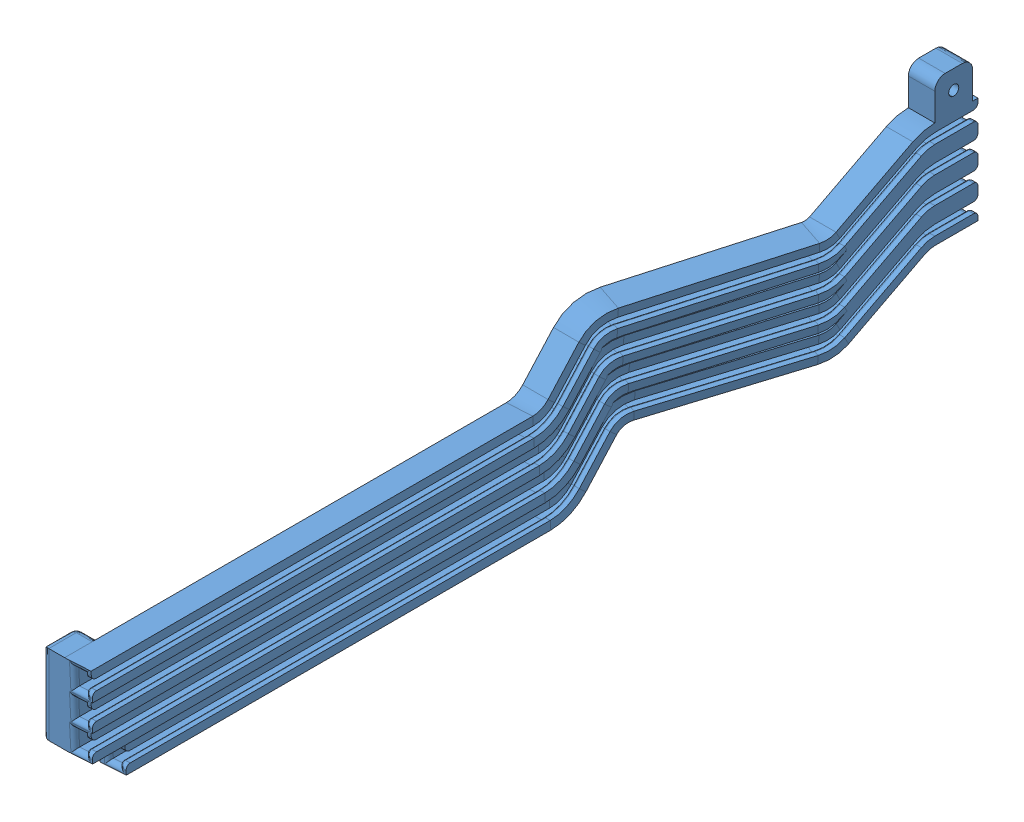
SolidWorks assembly cSL cap guide S1, configuration Default. Lengths in mm.
Overall size (29.52 72.96 242.8).
5 component instances, 2 part files, 4 mates.
Components (placement in the parent):
- cSL cap guides-1: cSL cap guides [11] at origin size (22.91 38.83 242.8) (hidden)
- cSL cap guides-2: cSL cap guides [12] at origin size (22.92 38.84 242.8) (hidden)
- cSL cap guides-3: cSL cap guides [13] at origin size (22.92 38.85 242.8) (hidden)
- cSL cap guides-4: cSL cap guides [14] at origin size (22.93 38.86 233) (hidden)
- csl cap guide s1^cSL cap guide S1-1: csl cap guide s1^cSL cap guide S1 [Default] at (-12.5 0 0) x (0 0 -1) z (1 0 0) size (242.8 72.96 29.52) (virtual)
Mates (geometry in assembly coordinates):
- InPlace1: in place: plane of ? through (-12.5 133.6 -652.4384) normal (1 0 0); plane of csl cap guide s1^cSL cap guide S1-1 through (-12.5 0 0) normal (1 0 0); moOrthogonalPlaneRef_w of ? through (-12.5 133.6 -652.4384) normal (1 0 0); line of csl cap guide s1^cSL cap guide S1-1 through (-55 -12.5 0) axis (0 0 1); plane of ? through (-12.5 133.6 -652.4384) normal (1 0 0); plane of csl cap guide s1^cSL cap guide S1-1 through (-12.5 0 0) normal (0 0 -1); plane of ? through (-12.5 133.6 -652.4384) normal (1 0 0); unknown of csl cap guide s1^cSL cap guide S1-1
- Coincident1: coincident aligned: plane of cSL cap guides-1; plane of ?
- Coincident2: coincident aligned: moOrthogonalPlaneRef_w of cSL cap guides-1 through (-12.5 0 0) normal (0 1 0); plane of csl cap guide s1^cSL cap guide S1-1
- Coincident3: coincident anti-aligned: moOrthogonalPlaneRef_w of cSL cap guides-1 through (-12.5 0 0) normal (0 0 1); plane of csl cap guide s1^cSL cap guide S1-1 through (-12.5 0 0) normal (0 0 -1)
